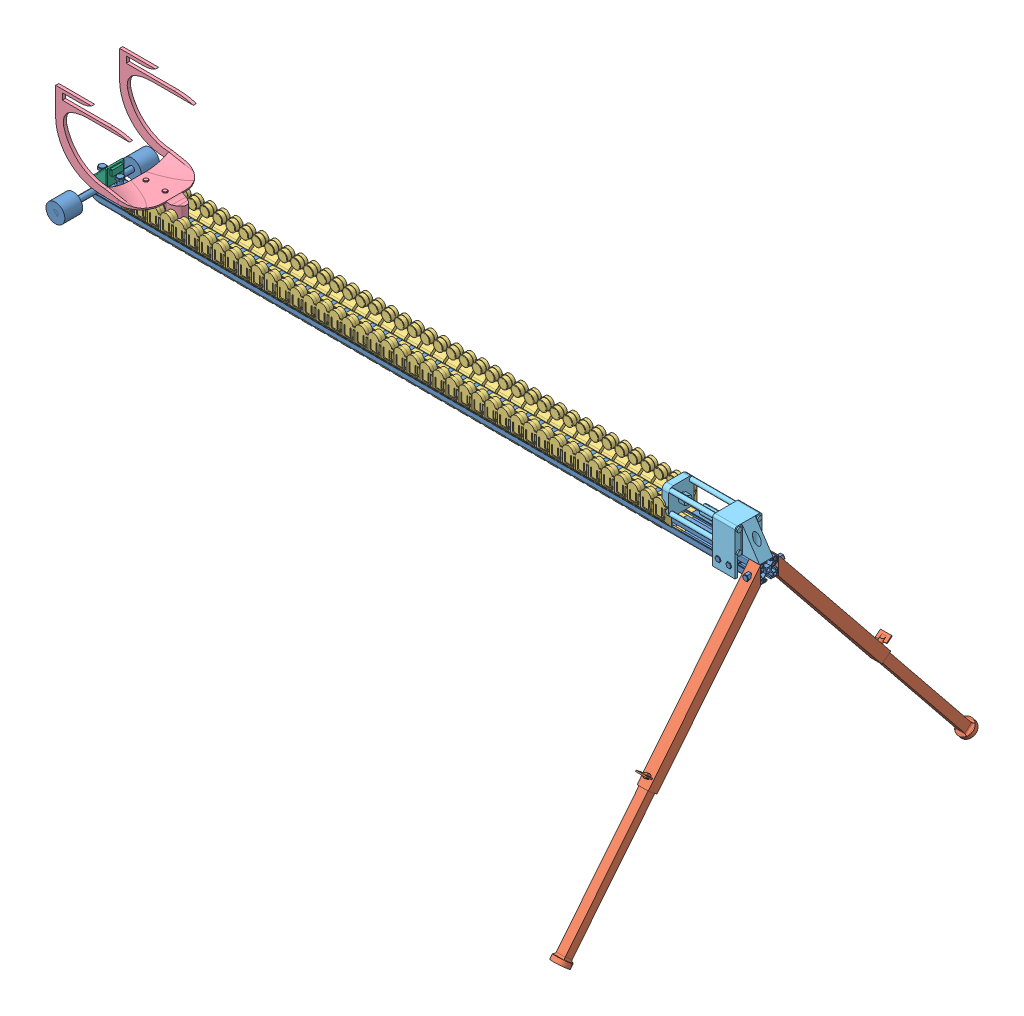
SolidWorks assembly Bütünleşik Montaj, configuration Varsayılan. Lengths in mm.
Overall size (1526.36 769.31 962.46).
91 component instances, 7 part files, 21 mates.
Components (placement in the parent):
- Sigma Profil Ray-2: Sigma Profil Ray [Default<As Machined>] at (-779.7244 -19.0314 -1441.6318) size (1509.85 59.06 212)
- Teleskobik Ayak-1: Teleskobik Ayak [Varsayılan] at (1209.7671 -320.0467 -1703.0407) x (0 -0.627693 0.778461) z (-1 0 0) size (50.67 710 36.34)
- Teleskobik Ayak-2: Teleskobik Ayak [Varsayılan] at (1209.7671 -320.0467 -1180.3477) x (0 -0.627693 -0.778461) z (1 0 0) size (50.67 710 36.34)
- Bobin ve Bobin Yuvası-1: Bobin ve Bobin Yuvası [Varsayılan] at (-145.5093 -20.4835 -1441.6942) x (0 0 1) z (-1 0 0) size (57 74.7 48.5)
- Taşıma Platformu-1: Taşıma Platformu [Varsayılan] at (-148.4244 3.0741 -1441.1142) x (0 -1 0) z (0 0 1) size (212.51 217.94 150)
- Bobin ve Bobin Yuvası-2: Bobin ve Bobin Yuvası [Varsayılan] at (-116.5093 -20.4835 -1441.6942) x (0 0 1) z (-1 0 0) size (57 74.7 48.5)
- Bobin ve Bobin Yuvası-3: Bobin ve Bobin Yuvası [Varsayılan] at (-87.5093 -20.4835 -1441.6942) x (0 0 1) z (-1 0 0) size (57 74.7 48.5)
- Bobin ve Bobin Yuvası-4: Bobin ve Bobin Yuvası [Varsayılan] at (-58.5093 -20.4835 -1441.6942) x (0 0 1) z (-1 0 0) size (57 74.7 48.5)
- Bobin ve Bobin Yuvası-5: Bobin ve Bobin Yuvası [Varsayılan] at (-29.5093 -20.4835 -1441.6942) x (0 0 1) z (-1 0 0) size (57 74.7 48.5)
- Bobin ve Bobin Yuvası-6: Bobin ve Bobin Yuvası [Varsayılan] at (-0.5093 -20.4835 -1441.6942) x (0 0 1) z (-1 0 0) size (57 74.7 48.5)
- Bobin ve Bobin Yuvası-7: Bobin ve Bobin Yuvası [Varsayılan] at (28.4907 -20.4835 -1441.6942) x (0 0 1) z (-1 0 0) size (57 74.7 48.5)
- Bobin ve Bobin Yuvası-8: Bobin ve Bobin Yuvası [Varsayılan] at (57.4907 -20.4835 -1441.6942) x (0 0 1) z (-1 0 0) size (57 74.7 48.5)
- Bobin ve Bobin Yuvası-9: Bobin ve Bobin Yuvası [Varsayılan] at (86.4907 -20.4835 -1441.6942) x (0 0 1) z (-1 0 0) size (57 74.7 48.5)
- Bobin ve Bobin Yuvası-10: Bobin ve Bobin Yuvası [Varsayılan] at (115.4907 -20.4835 -1441.6942) x (0 0 1) z (-1 0 0) size (57 74.7 48.5)
- Bobin ve Bobin Yuvası-11: Bobin ve Bobin Yuvası [Varsayılan] at (144.4907 -20.4835 -1441.6942) x (0 0 1) z (-1 0 0) size (57 74.7 48.5)
- Bobin ve Bobin Yuvası-12: Bobin ve Bobin Yuvası [Varsayılan] at (173.4907 -20.4835 -1441.6942) x (0 0 1) z (-1 0 0) size (57 74.7 48.5)
- Bobin ve Bobin Yuvası-13: Bobin ve Bobin Yuvası [Varsayılan] at (202.4907 -20.4835 -1441.6942) x (0 0 1) z (-1 0 0) size (57 74.7 48.5)
- Bobin ve Bobin Yuvası-14: Bobin ve Bobin Yuvası [Varsayılan] at (231.4907 -20.4835 -1441.6942) x (0 0 1) z (-1 0 0) size (57 74.7 48.5)
- Bobin ve Bobin Yuvası-15: Bobin ve Bobin Yuvası [Varsayılan] at (260.4907 -20.4835 -1441.6942) x (0 0 1) z (-1 0 0) size (57 74.7 48.5)
- Bobin ve Bobin Yuvası-16: Bobin ve Bobin Yuvası [Varsayılan] at (289.4907 -20.4835 -1441.6942) x (0 0 1) z (-1 0 0) size (57 74.7 48.5)
- Bobin ve Bobin Yuvası-17: Bobin ve Bobin Yuvası [Varsayılan] at (318.4907 -20.4835 -1441.6942) x (0 0 1) z (-1 0 0) size (57 74.7 48.5)
- Bobin ve Bobin Yuvası-18: Bobin ve Bobin Yuvası [Varsayılan] at (347.4907 -20.4835 -1441.6942) x (0 0 1) z (-1 0 0) size (57 74.7 48.5)
- Bobin ve Bobin Yuvası-19: Bobin ve Bobin Yuvası [Varsayılan] at (376.4907 -20.4835 -1441.6942) x (0 0 1) z (-1 0 0) size (57 74.7 48.5)
- Bobin ve Bobin Yuvası-20: Bobin ve Bobin Yuvası [Varsayılan] at (405.4907 -20.4835 -1441.6942) x (0 0 1) z (-1 0 0) size (57 74.7 48.5)
- Bobin ve Bobin Yuvası-21: Bobin ve Bobin Yuvası [Varsayılan] at (434.4907 -20.4835 -1441.6942) x (0 0 1) z (-1 0 0) size (57 74.7 48.5)
- Bobin ve Bobin Yuvası-22: Bobin ve Bobin Yuvası [Varsayılan] at (463.4907 -20.4835 -1441.6942) x (0 0 1) z (-1 0 0) size (57 74.7 48.5)
- Bobin ve Bobin Yuvası-23: Bobin ve Bobin Yuvası [Varsayılan] at (492.4907 -20.4835 -1441.6942) x (0 0 1) z (-1 0 0) size (57 74.7 48.5)
- Bobin ve Bobin Yuvası-24: Bobin ve Bobin Yuvası [Varsayılan] at (521.4907 -20.4835 -1441.6942) x (0 0 1) z (-1 0 0) size (57 74.7 48.5)
- Bobin ve Bobin Yuvası-25: Bobin ve Bobin Yuvası [Varsayılan] at (550.4907 -20.4835 -1441.6942) x (0 0 1) z (-1 0 0) size (57 74.7 48.5)
- Bobin ve Bobin Yuvası-26: Bobin ve Bobin Yuvası [Varsayılan] at (579.4907 -20.4835 -1441.6942) x (0 0 1) z (-1 0 0) size (57 74.7 48.5)
- Bobin ve Bobin Yuvası-27: Bobin ve Bobin Yuvası [Varsayılan] at (608.4907 -20.4835 -1441.6942) x (0 0 1) z (-1 0 0) size (57 74.7 48.5)
- Bobin ve Bobin Yuvası-28: Bobin ve Bobin Yuvası [Varsayılan] at (637.4907 -20.4835 -1441.6942) x (0 0 1) z (-1 0 0) size (57 74.7 48.5)
- Bobin ve Bobin Yuvası-29: Bobin ve Bobin Yuvası [Varsayılan] at (666.4907 -20.4835 -1441.6942) x (0 0 1) z (-1 0 0) size (57 74.7 48.5)
- Bobin ve Bobin Yuvası-30: Bobin ve Bobin Yuvası [Varsayılan] at (695.4907 -20.4835 -1441.6942) x (0 0 1) z (-1 0 0) size (57 74.7 48.5)
- Bobin ve Bobin Yuvası-31: Bobin ve Bobin Yuvası [Varsayılan] at (724.4907 -20.4835 -1441.6942) x (0 0 1) z (-1 0 0) size (57 74.7 48.5)
- Bobin ve Bobin Yuvası-32: Bobin ve Bobin Yuvası [Varsayılan] at (753.4907 -20.4835 -1441.6942) x (0 0 1) z (-1 0 0) size (57 74.7 48.5)
- Bobin ve Bobin Yuvası-33: Bobin ve Bobin Yuvası [Varsayılan] at (782.4907 -20.4835 -1441.6942) x (0 0 1) z (-1 0 0) size (57 74.7 48.5)
- Bobin ve Bobin Yuvası-34: Bobin ve Bobin Yuvası [Varsayılan] at (811.4907 -20.4835 -1441.6942) x (0 0 1) z (-1 0 0) size (57 74.7 48.5)
- Bobin ve Bobin Yuvası-35: Bobin ve Bobin Yuvası [Varsayılan] at (840.4907 -20.4835 -1441.6942) x (0 0 1) z (-1 0 0) size (57 74.7 48.5)
- Bobin ve Bobin Yuvası-36: Bobin ve Bobin Yuvası [Varsayılan] at (869.4907 -20.4835 -1441.6942) x (0 0 1) z (-1 0 0) size (57 74.7 48.5)
- Bobin ve Bobin Yuvası-37: Bobin ve Bobin Yuvası [Varsayılan] at (898.4907 -20.4835 -1441.6942) x (0 0 1) z (-1 0 0) size (57 74.7 48.5)
- Bobin ve Bobin Yuvası-38: Bobin ve Bobin Yuvası [Varsayılan] at (927.4907 -20.4835 -1441.6942) x (0 0 1) z (-1 0 0) size (57 74.7 48.5)
- Bobin ve Bobin Yuvası-39: Bobin ve Bobin Yuvası [Varsayılan] at (956.4907 -20.4835 -1441.6942) x (0 0 1) z (-1 0 0) size (57 74.7 48.5)
- Bobin ve Bobin Yuvası-40: Bobin ve Bobin Yuvası [Varsayılan] at (985.4907 -20.4835 -1441.6942) x (0 0 1) z (-1 0 0) size (57 74.7 48.5)
- Bobin ve Bobin Yuvası-41: Bobin ve Bobin Yuvası [Varsayılan] at (1014.4907 -20.4835 -1441.6942) x (0 0 1) z (-1 0 0) size (57 74.7 48.5)
- Bobin ve Bobin Yuvası-42: Bobin ve Bobin Yuvası [Varsayılan] at (1043.4907 -20.4835 -1441.6942) x (0 0 1) z (-1 0 0) size (57 74.7 48.5)
- Darbe Emici-2: Darbe Emici [Varsayılan] at (1130.2756 29.4165 -1436.6942) x (0 -1 0) z (1 0 0) size (100 60 205)
- optik_sensörü-2: optik_sensörü [Varsayılan] at (-239.7244 -0.5835 -1441.6942) x (0 0 -1) z (1 0 0) size (40 37.17 45)
- Bobin ve Bobin Yuvası-43: Bobin ve Bobin Yuvası [Varsayılan] at (-209.4244 -21.6259 -1441.6942) x (0 0 -1) z (1 0 0) size (57 74.7 48.5)
- Bobin ve Bobin Yuvası-44: Bobin ve Bobin Yuvası [Varsayılan] at (-180.4244 -21.6259 -1441.6942) x (0 0 -1) z (1 0 0) size (57 74.7 48.5)
- Bobin ve Bobin Yuvası-45: Bobin ve Bobin Yuvası [Varsayılan] at (-151.4244 -21.6259 -1441.6942) x (0 0 -1) z (1 0 0) size (57 74.7 48.5)
- Bobin ve Bobin Yuvası-46: Bobin ve Bobin Yuvası [Varsayılan] at (-122.4244 -21.6259 -1441.6942) x (0 0 -1) z (1 0 0) size (57 74.7 48.5)
- Bobin ve Bobin Yuvası-47: Bobin ve Bobin Yuvası [Varsayılan] at (-93.4244 -21.6259 -1441.6942) x (0 0 -1) z (1 0 0) size (57 74.7 48.5)
- Bobin ve Bobin Yuvası-48: Bobin ve Bobin Yuvası [Varsayılan] at (-64.4244 -21.6259 -1441.6942) x (0 0 -1) z (1 0 0) size (57 74.7 48.5)
- Bobin ve Bobin Yuvası-49: Bobin ve Bobin Yuvası [Varsayılan] at (-35.4244 -21.6259 -1441.6942) x (0 0 -1) z (1 0 0) size (57 74.7 48.5)
- Bobin ve Bobin Yuvası-50: Bobin ve Bobin Yuvası [Varsayılan] at (-6.4244 -21.6259 -1441.6942) x (0 0 -1) z (1 0 0) size (57 74.7 48.5)
- Bobin ve Bobin Yuvası-51: Bobin ve Bobin Yuvası [Varsayılan] at (22.5756 -21.6259 -1441.6942) x (0 0 -1) z (1 0 0) size (57 74.7 48.5)
- Bobin ve Bobin Yuvası-52: Bobin ve Bobin Yuvası [Varsayılan] at (51.5756 -21.6259 -1441.6942) x (0 0 -1) z (1 0 0) size (57 74.7 48.5)
- Bobin ve Bobin Yuvası-53: Bobin ve Bobin Yuvası [Varsayılan] at (80.5756 -21.6259 -1441.6942) x (0 0 -1) z (1 0 0) size (57 74.7 48.5)
- Bobin ve Bobin Yuvası-54: Bobin ve Bobin Yuvası [Varsayılan] at (109.5756 -21.6259 -1441.6942) x (0 0 -1) z (1 0 0) size (57 74.7 48.5)
- Bobin ve Bobin Yuvası-55: Bobin ve Bobin Yuvası [Varsayılan] at (138.5756 -21.6259 -1441.6942) x (0 0 -1) z (1 0 0) size (57 74.7 48.5)
- Bobin ve Bobin Yuvası-56: Bobin ve Bobin Yuvası [Varsayılan] at (167.5756 -21.6259 -1441.6942) x (0 0 -1) z (1 0 0) size (57 74.7 48.5)
- Bobin ve Bobin Yuvası-57: Bobin ve Bobin Yuvası [Varsayılan] at (196.5756 -21.6259 -1441.6942) x (0 0 -1) z (1 0 0) size (57 74.7 48.5)
- Bobin ve Bobin Yuvası-58: Bobin ve Bobin Yuvası [Varsayılan] at (225.5756 -21.6259 -1441.6942) x (0 0 -1) z (1 0 0) size (57 74.7 48.5)
- Bobin ve Bobin Yuvası-59: Bobin ve Bobin Yuvası [Varsayılan] at (254.5756 -21.6259 -1441.6942) x (0 0 -1) z (1 0 0) size (57 74.7 48.5)
- Bobin ve Bobin Yuvası-60: Bobin ve Bobin Yuvası [Varsayılan] at (283.5756 -21.6259 -1441.6942) x (0 0 -1) z (1 0 0) size (57 74.7 48.5)
- Bobin ve Bobin Yuvası-61: Bobin ve Bobin Yuvası [Varsayılan] at (312.5756 -21.6259 -1441.6942) x (0 0 -1) z (1 0 0) size (57 74.7 48.5)
- Bobin ve Bobin Yuvası-62: Bobin ve Bobin Yuvası [Varsayılan] at (341.5756 -21.6259 -1441.6942) x (0 0 -1) z (1 0 0) size (57 74.7 48.5)
- Bobin ve Bobin Yuvası-63: Bobin ve Bobin Yuvası [Varsayılan] at (370.5756 -21.6259 -1441.6942) x (0 0 -1) z (1 0 0) size (57 74.7 48.5)
- Bobin ve Bobin Yuvası-64: Bobin ve Bobin Yuvası [Varsayılan] at (399.5756 -21.6259 -1441.6942) x (0 0 -1) z (1 0 0) size (57 74.7 48.5)
- Bobin ve Bobin Yuvası-65: Bobin ve Bobin Yuvası [Varsayılan] at (428.5756 -21.6259 -1441.6942) x (0 0 -1) z (1 0 0) size (57 74.7 48.5)
- Bobin ve Bobin Yuvası-66: Bobin ve Bobin Yuvası [Varsayılan] at (457.5756 -21.6259 -1441.6942) x (0 0 -1) z (1 0 0) size (57 74.7 48.5)
- Bobin ve Bobin Yuvası-67: Bobin ve Bobin Yuvası [Varsayılan] at (486.5756 -21.6259 -1441.6942) x (0 0 -1) z (1 0 0) size (57 74.7 48.5)
- Bobin ve Bobin Yuvası-68: Bobin ve Bobin Yuvası [Varsayılan] at (515.5756 -21.6259 -1441.6942) x (0 0 -1) z (1 0 0) size (57 74.7 48.5)
- Bobin ve Bobin Yuvası-69: Bobin ve Bobin Yuvası [Varsayılan] at (544.5756 -21.6259 -1441.6942) x (0 0 -1) z (1 0 0) size (57 74.7 48.5)
- Bobin ve Bobin Yuvası-70: Bobin ve Bobin Yuvası [Varsayılan] at (573.5756 -21.6259 -1441.6942) x (0 0 -1) z (1 0 0) size (57 74.7 48.5)
- Bobin ve Bobin Yuvası-71: Bobin ve Bobin Yuvası [Varsayılan] at (602.5756 -21.6259 -1441.6942) x (0 0 -1) z (1 0 0) size (57 74.7 48.5)
- Bobin ve Bobin Yuvası-72: Bobin ve Bobin Yuvası [Varsayılan] at (631.5756 -21.6259 -1441.6942) x (0 0 -1) z (1 0 0) size (57 74.7 48.5)
- Bobin ve Bobin Yuvası-73: Bobin ve Bobin Yuvası [Varsayılan] at (660.5756 -21.6259 -1441.6942) x (0 0 -1) z (1 0 0) size (57 74.7 48.5)
- Bobin ve Bobin Yuvası-74: Bobin ve Bobin Yuvası [Varsayılan] at (689.5756 -21.6259 -1441.6942) x (0 0 -1) z (1 0 0) size (57 74.7 48.5)
- Bobin ve Bobin Yuvası-75: Bobin ve Bobin Yuvası [Varsayılan] at (718.5756 -21.6259 -1441.6942) x (0 0 -1) z (1 0 0) size (57 74.7 48.5)
- Bobin ve Bobin Yuvası-76: Bobin ve Bobin Yuvası [Varsayılan] at (747.5756 -21.6259 -1441.6942) x (0 0 -1) z (1 0 0) size (57 74.7 48.5)
- Bobin ve Bobin Yuvası-77: Bobin ve Bobin Yuvası [Varsayılan] at (776.5756 -21.6259 -1441.6942) x (0 0 -1) z (1 0 0) size (57 74.7 48.5)
- Bobin ve Bobin Yuvası-78: Bobin ve Bobin Yuvası [Varsayılan] at (805.5756 -21.6259 -1441.6942) x (0 0 -1) z (1 0 0) size (57 74.7 48.5)
- Bobin ve Bobin Yuvası-79: Bobin ve Bobin Yuvası [Varsayılan] at (834.5756 -21.6259 -1441.6942) x (0 0 -1) z (1 0 0) size (57 74.7 48.5)
- Bobin ve Bobin Yuvası-80: Bobin ve Bobin Yuvası [Varsayılan] at (863.5756 -21.6259 -1441.6942) x (0 0 -1) z (1 0 0) size (57 74.7 48.5)
- Bobin ve Bobin Yuvası-81: Bobin ve Bobin Yuvası [Varsayılan] at (892.5756 -21.6259 -1441.6942) x (0 0 -1) z (1 0 0) size (57 74.7 48.5)
- Bobin ve Bobin Yuvası-82: Bobin ve Bobin Yuvası [Varsayılan] at (921.5756 -21.6259 -1441.6942) x (0 0 -1) z (1 0 0) size (57 74.7 48.5)
- Bobin ve Bobin Yuvası-83: Bobin ve Bobin Yuvası [Varsayılan] at (950.5756 -21.6259 -1441.6942) x (0 0 -1) z (1 0 0) size (57 74.7 48.5)
- Bobin ve Bobin Yuvası-84: Bobin ve Bobin Yuvası [Varsayılan] at (979.5756 -21.6259 -1441.6942) x (0 0 -1) z (1 0 0) size (57 74.7 48.5)
- Assem4 Mini Talon-2: Assem4 Mini Talon [Varsayılan] at (-218.237 173.9182 -630.943) x (-0.999508 -0.03136 0) z (0 0 -1) (suppressed, hidden)
Mates (geometry in assembly coordinates):
- Eş Merkezli1: concentric anti-aligned: cylinder of Sigma Profil Ray-2 through (1209.7671 -20.6445 -1407.6942) axis (0 0 -1) radius 1; cylinder of Teleskobik Ayak-1 through (1209.7671 -20.6445 -1493.6942) axis (0 0 1) radius 5
- Çakışık1: coincident anti-aligned: plane of Sigma Profil Ray-2 through (1220.2756 -15.4835 -1461.6942) normal (0 0 -1); plane of Teleskobik Ayak-1 through (1164.2671 -0.8161 -1461.6942) normal (0 0 1)
- Paralel1: parallel aligned: plane of Sigma Profil Ray-2 through (1220.2756 -5.0835 -1426.1942) normal (1 0 0); plane of Teleskobik Ayak-1 through (1222.2671 -0.8161 -1461.6942) normal (1 0 0)
- Eş Merkezli3: concentric aligned: cylinder of Sigma Profil Ray-2 through (1209.7671 -20.6445 -1407.6942) axis (0 0 -1) radius 1; cylinder of Teleskobik Ayak-2 through (1209.7671 -20.6445 -1389.6942) axis (0 0 -1) radius 5
- Çakışık3: coincident anti-aligned: plane of Sigma Profil Ray-2 through (1220.2756 -15.4835 -1421.6942) normal (0 0 1); plane of Teleskobik Ayak-2 through (1255.2671 -0.8161 -1421.6942) normal (0 0 -1)
- Paralel2: parallel aligned: plane of Sigma Profil Ray-2 through (1220.2756 -5.0835 -1426.1942) normal (1 0 0); plane of Teleskobik Ayak-2 through (1222.2671 -0.8161 -1421.6942) normal (1 0 0)
- Çakışık5: coincident anti-aligned: plane of Sigma Profil Ray-2 through (1220.2756 -15.4835 -1461.6942) normal (0 0 -1); plane of Bobin ve Bobin Yuvası-1 through (-189.5093 -4.9835 -1461.6942) normal (0 0 1)
- Uzaklık1: distance = 15 mm: line of Bobin ve Bobin Yuvası-1 through (-189.5093 -25.5835 -1461.6942) axis (1 0 0); plane of Sigma Profil Ray-2 through (1220.2756 -40.5835 -1457.1942) normal (0 -1 0)
- Paralel3: parallel anti-aligned: plane of Sigma Profil Ray-2 through (1220.2756 -0.5835 -1457.1942) normal (0 1 0); plane of Taşıma Platformu-1 through (-164.9344 -0.5835 -1448.7342) normal (0 -1 0)
- Çakışık8: coincident anti-aligned: plane of Sigma Profil Ray-2 through (1220.2756 -0.5835 -1457.1942) normal (0 1 0); plane of Taşıma Platformu-1 through (-164.9344 -0.5835 -1448.7342) normal (0 -1 0)
- Uzaklık2: distance = 6 mm anti-aligned: plane of Sigma Profil Ray-2 through (1220.2756 -8.7693 -1431.2942) normal (0 0 -1); plane of Taşıma Platformu-1 through (-84.5394 -4.5459 -1437.2942) normal (0 0 1)
- Çakışık10: coincident anti-aligned: plane of Sigma Profil Ray-2 through (1220.2756 -0.5835 -1426.1942) normal (0 1 0); plane of Darbe Emici-2 through (1180.2756 -0.5835 -1466.6942) normal (0 -1 0)
- Çakışık11: coincident anti-aligned: line of Sigma Profil Ray-2 through (1220.2756 -0.5835 -1457.1942) axis (0 0 1); line of Darbe Emici-2 through (1220.2756 -0.5835 -1421.6942) axis (0 0 -1)
- Çakışık12: coincident anti-aligned: plane of Sigma Profil Ray-2 through (1220.2756 -15.4835 -1461.6942) normal (0 0 -1); plane of Darbe Emici-2 through (1130.2756 29.4165 -1461.6942) normal (0 0 1)
- Çakışık14: coincident anti-aligned: plane of Sigma Profil Ray-2 through (1220.2756 -0.5835 -1457.1942) normal (0 1 0); plane of optik_sensörü-2 through (-239.7244 -0.5835 -1421.6942) normal (0 -1 0)
- Çakışık15: coincident aligned: line of Sigma Profil Ray-2 through (-279.7244 -0.5835 -1446.7942) axis (0 0 -1); line of optik_sensörü-2 through (-279.7244 -0.5835 -1423.6942) axis (0 0 -1)
- Çakışık16: coincident aligned: plane of Sigma Profil Ray-2 through (1220.2756 -15.4835 -1461.6942) normal (0 0 -1); plane of optik_sensörü-2 through (-239.7244 -0.5835 -1461.6942) normal (0 0 -1)
- Çakışık17: coincident anti-aligned: plane of Sigma Profil Ray-2 through (1220.2756 -15.4835 -1421.6942) normal (0 0 1); plane of Bobin ve Bobin Yuvası-43 through (-165.4244 -6.1259 -1421.6942) normal (0 0 -1)
- Uzaklık3: distance = 90.3 mm aligned: plane of Bobin ve Bobin Yuvası-43 through (-189.4244 -21.6259 -1441.6942) normal (-1 0 0); plane of Sigma Profil Ray-2 through (-279.7244 -19.0314 -1441.6318) normal (-1 0 0)
- Eş Merkezli4: concentric anti-aligned: cylinder of Taşıma Platformu-1 through (-177.4244 21.0741 -1421.1142) axis (0 0 -1) radius 10; cylinder of Bobin ve Bobin Yuvası-43 through (-177.4244 21.0741 -1420.6942) axis (0 0 1) radius 11.0756
- Paralel5: parallel aligned: plane of Sigma Profil Ray-2 through (-268.5182 -20.5835 -1335.6942) normal (0 0 1); plane of Assem4 Mini Talon-2 through (-73.6045 198.8593 -1413.307) normal (0 0 1)
